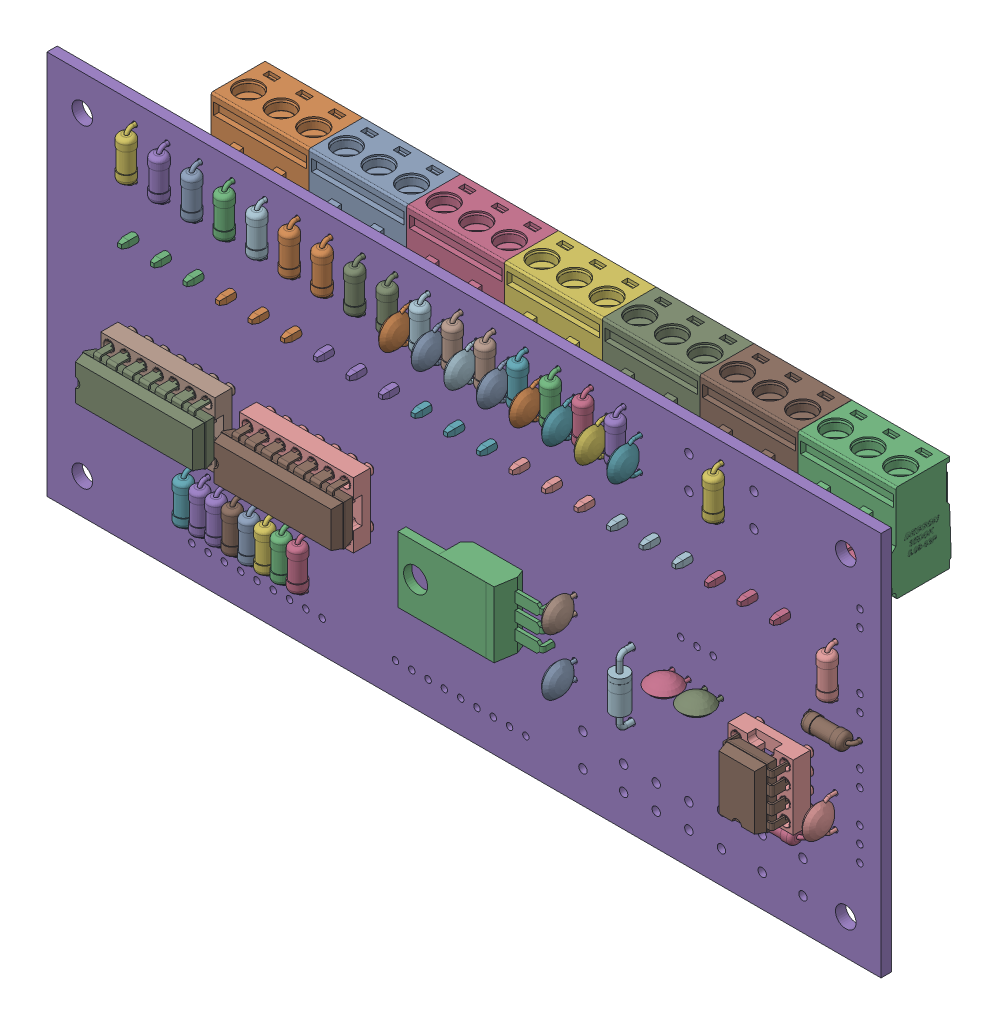
SolidWorks assembly minilab.step, configuration Predeterminado. Lengths in mm.
Overall size (130 60 30.78).
129 component instances, 13 part files, 0 mates.
Components (placement in the parent):
- C_Disc_D5.0mm_W2.5mm_P2.50mm.step-1: C_Disc_D5.0mm_W2.5mm_P2.50mm.step [Predeterminado] at (175.26 -113.03 1.65) x (0 -1 0) z (0 0 1) size (5 2.5 7.1)
  - SOLID.step-1: SOLID.step [Predeterminado] at origin size (5 2.5 7.1)
- C_Disc_D5.0mm_W2.5mm_P5.00mm.step-1: C_Disc_D5.0mm_W2.5mm_P5.00mm.step [Predeterminado] at (170.18 -82.55 1.65) x (0 1 0) z (0 0 1) size (5.5 2.5 7.1)
  - SOLID-0.step-1: SOLID-0.step [Predeterminado] at origin size (5.5 2.5 7.1)
- R_Axial_DIN0207_L6.3mm_D2.5mm_P7.62mm_Horizontal.step-1: R_Axial_DIN0207_L6.3mm_D2.5mm_P7.62mm_Horizontal.step [Predeterminado] at (121.92 -82.55 1.65) x (0 1 0) z (0 0 1) size (8.22 2.5 5.5)
  - SOLID-1.step-1: SOLID-1.step [Predeterminado] at origin size (8.22 2.5 5.5)
- C_Disc_D5.0mm_W2.5mm_P2.50mm.step_2-1: C_Disc_D5.0mm_W2.5mm_P2.50mm.step_2 [Predeterminado] at (190.52 -106.68 1.65) size (5 2.5 7.1)
  - SOLID.step-1: SOLID.step [Predeterminado] at origin size (5 2.5 7.1)
- R_Axial_DIN0207_L6.3mm_D2.5mm_P7.62mm_Horizontal.step_2-1: R_Axial_DIN0207_L6.3mm_D2.5mm_P7.62mm_Horizontal.step_2 [Predeterminado] at (182.88 -74.93 1.65) x (0 -1 0) z (0 0 1) size (8.22 2.5 5.5)
  - SOLID-1.step-1: SOLID-1.step [Predeterminado] at origin size (8.22 2.5 5.5)
- R_Axial_DIN0207_L6.3mm_D2.5mm_P7.62mm_Horizontal.step_3-1: R_Axial_DIN0207_L6.3mm_D2.5mm_P7.62mm_Horizontal.step_3 [Predeterminado] at (198.12 -82.55 1.65) x (0 1 0) z (0 0 1) size (8.22 2.5 5.5)
  - SOLID-1.step-1: SOLID-1.step [Predeterminado] at origin size (8.22 2.5 5.5)
- C_Disc_D5.0mm_W2.5mm_P5.00mm.step_2-1: C_Disc_D5.0mm_W2.5mm_P5.00mm.step_2 [Predeterminado] at (175.26 -82.51 1.65) x (0 1 0) z (0 0 1) size (5.5 2.5 7.1)
  - SOLID-0.step-1: SOLID-0.step [Predeterminado] at origin size (5.5 2.5 7.1)
- DIP-14_W7.62mm_Socket.step-1: DIP-14_W7.62mm_Socket.step [Predeterminado] at (106.675 -110.48 1.65) x (0 1 0) z (0 0 1) size (10.16 17.78 7.79)
  - SOLID-2.step-1: SOLID-2.step [Predeterminado] at origin size (10.16 17.78 7.79)
- DIP-14_W7.62mm.step-1: DIP-14_W7.62mm.step [Predeterminado] at (106.675 -110.48 5.65) x (0 1 0) z (0 0 1) size (7.87 19.05 6.98)
  - SOLID-3.step-1: SOLID-3.step [Predeterminado] at origin size (7.87 19.05 6.98)
- DIP-8_W7.62mm_Socket.step-1: DIP-8_W7.62mm_Socket.step [Predeterminado] at (212.06 -114.3 1.65) x (-1 0 0) z (0 0 1) size (10.16 10.16 7.79)
  - SOLID-4.step-1: SOLID-4.step [Predeterminado] at origin size (10.16 10.16 7.79)
- DIP-8_W7.62mm.step-1: DIP-8_W7.62mm.step [Predeterminado] at (212.06 -114.3 5.65) x (-1 0 0) z (0 0 1) size (7.87 9.27 6.98)
  - SOLID-5.step-1: SOLID-5.step [Predeterminado] at origin size (7.87 9.27 6.98)
- R_Axial_DIN0207_L6.3mm_D2.5mm_P7.62mm_Horizontal.step_4-1: R_Axial_DIN0207_L6.3mm_D2.5mm_P7.62mm_Horizontal.step_4 [Predeterminado] at (127 -82.55 1.65) x (0 1 0) z (0 0 1) size (8.22 2.5 5.5)
  - SOLID-1.step-1: SOLID-1.step [Predeterminado] at origin size (8.22 2.5 5.5)
- R_Axial_DIN0207_L6.3mm_D2.5mm_P7.62mm_Horizontal.step_5-1: R_Axial_DIN0207_L6.3mm_D2.5mm_P7.62mm_Horizontal.step_5 [Predeterminado] at (125.73 -116.84 1.65) x (0 -1 0) z (0 0 1) size (8.22 2.5 5.5)
  - SOLID-1.step-1: SOLID-1.step [Predeterminado] at origin size (8.22 2.5 5.5)
- C_Disc_D5.0mm_W2.5mm_P5.00mm.step_3-1: C_Disc_D5.0mm_W2.5mm_P5.00mm.step_3 [Predeterminado] at (149.86 -82.55 1.65) x (0 1 0) z (0 0 1) size (5.5 2.5 7.1)
  - SOLID-0.step-1: SOLID-0.step [Predeterminado] at origin size (5.5 2.5 7.1)
- TO-220-3_Horizontal_TabUp.step-1: TO-220-3_Horizontal_TabUp.step [Predeterminado] at (171.66 -107.46 1.65) x (0 -1 0) z (0 0 1) size (10.25 19.74 12.58)
  - SOLID-6.step-1: SOLID-6.step [Predeterminado] at origin size (10.25 19.74 12.58)
- R_Axial_DIN0207_L6.3mm_D2.5mm_P7.62mm_Horizontal.step_6-1: R_Axial_DIN0207_L6.3mm_D2.5mm_P7.62mm_Horizontal.step_6 [Predeterminado] at (133.35 -116.84 1.65) x (0 -1 0) z (0 0 1) size (8.22 2.5 5.5)
  - SOLID-1.step-1: SOLID-1.step [Predeterminado] at origin size (8.22 2.5 5.5)
- R_Axial_DIN0207_L6.3mm_D2.5mm_P7.62mm_Horizontal.step_7-1: R_Axial_DIN0207_L6.3mm_D2.5mm_P7.62mm_Horizontal.step_7 [Predeterminado] at (120.65 -116.84 1.65) x (0 -1 0) z (0 0 1) size (8.22 2.5 5.5)
  - SOLID-1.step-1: SOLID-1.step [Predeterminado] at origin size (8.22 2.5 5.5)
- C_Disc_D5.0mm_W2.5mm_P5.00mm.step_4-1: C_Disc_D5.0mm_W2.5mm_P5.00mm.step_4 [Predeterminado] at (180.34 -82.51 1.65) x (0 1 0) z (0 0 1) size (5.5 2.5 7.1)
  - SOLID-0.step-1: SOLID-0.step [Predeterminado] at origin size (5.5 2.5 7.1)
- R_Axial_DIN0207_L6.3mm_D2.5mm_P7.62mm_Horizontal.step_8-1: R_Axial_DIN0207_L6.3mm_D2.5mm_P7.62mm_Horizontal.step_8 [Predeterminado] at (115.57 -116.84 1.65) x (0 -1 0) z (0 0 1) size (8.22 2.5 5.5)
  - SOLID-1.step-1: SOLID-1.step [Predeterminado] at origin size (8.22 2.5 5.5)
- R_Axial_DIN0207_L6.3mm_D2.5mm_P7.62mm_Horizontal.step_9-1: R_Axial_DIN0207_L6.3mm_D2.5mm_P7.62mm_Horizontal.step_9 [Predeterminado] at (157.48 -74.93 1.65) x (0 -1 0) z (0 0 1) size (8.22 2.5 5.5)
  - SOLID-1.step-1: SOLID-1.step [Predeterminado] at origin size (8.22 2.5 5.5)
- R_Axial_DIN0207_L6.3mm_D2.5mm_P7.62mm_Horizontal.step_10-1: R_Axial_DIN0207_L6.3mm_D2.5mm_P7.62mm_Horizontal.step_10 [Predeterminado] at (142.24 -82.55 1.65) x (0 1 0) z (0 0 1) size (8.22 2.5 5.5)
  - SOLID-1.step-1: SOLID-1.step [Predeterminado] at origin size (8.22 2.5 5.5)
- C_Disc_D5.0mm_W2.5mm_P5.00mm.step_5-1: C_Disc_D5.0mm_W2.5mm_P5.00mm.step_5 [Predeterminado] at (215.88 -110.54 1.65) x (0 -1 0) z (0 0 1) size (5.5 2.5 7.1)
  - SOLID-0.step-1: SOLID-0.step [Predeterminado] at origin size (5.5 2.5 7.1)
- R_Axial_DIN0207_L6.3mm_D2.5mm_P7.62mm_Horizontal.step_11-1: R_Axial_DIN0207_L6.3mm_D2.5mm_P7.62mm_Horizontal.step_11 [Predeterminado] at (123.19 -116.84 1.65) x (0 -1 0) z (0 0 1) size (8.22 2.5 5.5)
  - SOLID-1.step-1: SOLID-1.step [Predeterminado] at origin size (8.22 2.5 5.5)
- D_DO-41_SOD81_P10.16mm_Horizontal.step-1: D_DO-41_SOD81_P10.16mm_Horizontal.step [Predeterminado] at (184.15 -106.68 1.65) x (0 -1 0) z (0 0 1) size (10.96 2.72 5.71)
  - SOLID-7.step-1: SOLID-7.step [Predeterminado] at origin size (10.96 2.72 5.71)
- R_Axial_DIN0207_L6.3mm_D2.5mm_P7.62mm_Horizontal.step_12-1: R_Axial_DIN0207_L6.3mm_D2.5mm_P7.62mm_Horizontal.step_12 [Predeterminado] at (116.84 -82.55 1.65) x (0 1 0) z (0 0 1) size (8.22 2.5 5.5)
  - SOLID-1.step-1: SOLID-1.step [Predeterminado] at origin size (8.22 2.5 5.5)
- R_Axial_DIN0207_L6.3mm_D2.5mm_P7.62mm_Horizontal.step_13-1: R_Axial_DIN0207_L6.3mm_D2.5mm_P7.62mm_Horizontal.step_13 [Predeterminado] at (132.08 -82.55 1.65) x (0 1 0) z (0 0 1) size (8.22 2.5 5.5)
  - SOLID-1.step-1: SOLID-1.step [Predeterminado] at origin size (8.22 2.5 5.5)
- R_Axial_DIN0207_L6.3mm_D2.5mm_P7.62mm_Horizontal.step_14-1: R_Axial_DIN0207_L6.3mm_D2.5mm_P7.62mm_Horizontal.step_14 [Predeterminado] at (172.72 -74.93 1.65) x (0 -1 0) z (0 0 1) size (8.22 2.5 5.5)
  - SOLID-1.step-1: SOLID-1.step [Predeterminado] at origin size (8.22 2.5 5.5)
- R_Axial_DIN0207_L6.3mm_D2.5mm_P7.62mm_Horizontal.step_15-1: R_Axial_DIN0207_L6.3mm_D2.5mm_P7.62mm_Horizontal.step_15 [Predeterminado] at (177.8 -74.93 1.65) x (0 -1 0) z (0 0 1) size (8.22 2.5 5.5)
  - SOLID-1.step-1: SOLID-1.step [Predeterminado] at origin size (8.22 2.5 5.5)
- R_Axial_DIN0207_L6.3mm_D2.5mm_P7.62mm_Horizontal.step_16-1: R_Axial_DIN0207_L6.3mm_D2.5mm_P7.62mm_Horizontal.step_16 [Predeterminado] at (111.76 -82.55 1.65) x (0 1 0) z (0 0 1) size (8.22 2.5 5.5)
  - SOLID-1.step-1: SOLID-1.step [Predeterminado] at origin size (8.22 2.5 5.5)
- R_Axial_DIN0207_L6.3mm_D2.5mm_P7.62mm_Horizontal.step_17-1: R_Axial_DIN0207_L6.3mm_D2.5mm_P7.62mm_Horizontal.step_17 [Predeterminado] at (128.27 -116.84 1.65) x (0 -1 0) z (0 0 1) size (8.22 2.5 5.5)
  - SOLID-1.step-1: SOLID-1.step [Predeterminado] at origin size (8.22 2.5 5.5)
- C_Disc_D5.0mm_W2.5mm_P5.00mm.step_6-1: C_Disc_D5.0mm_W2.5mm_P5.00mm.step_6 [Predeterminado] at (185.42 -82.51 1.65) x (0 1 0) z (0 0 1) size (5.5 2.5 7.1)
  - SOLID-0.step-1: SOLID-0.step [Predeterminado] at origin size (5.5 2.5 7.1)
- C_Disc_D5.0mm_W2.5mm_P2.50mm.step_3-1: C_Disc_D5.0mm_W2.5mm_P2.50mm.step_3 [Predeterminado] at (175.26 -106.68 1.65) x (0 1 0) z (0 0 1) size (5 2.5 7.1)
  - SOLID.step-1: SOLID.step [Predeterminado] at origin size (5 2.5 7.1)
- C_Disc_D5.0mm_W2.5mm_P2.50mm.step_4-1: C_Disc_D5.0mm_W2.5mm_P2.50mm.step_4 [Predeterminado] at (198.08 -106.68 1.65) x (-1 0 0) z (0 0 1) size (5 2.5 7.1)
  - SOLID.step-1: SOLID.step [Predeterminado] at origin size (5 2.5 7.1)
- R_Axial_DIN0207_L6.3mm_D2.5mm_P7.62mm_Horizontal.step_18-1: R_Axial_DIN0207_L6.3mm_D2.5mm_P7.62mm_Horizontal.step_18 [Predeterminado] at (215.9 -90.17 1.65) x (0 -1 0) z (0 0 1) size (8.22 2.5 5.5)
  - SOLID-1.step-1: SOLID-1.step [Predeterminado] at origin size (8.22 2.5 5.5)
- R_Axial_DIN0207_L6.3mm_D2.5mm_P7.62mm_Horizontal.step_19-1: R_Axial_DIN0207_L6.3mm_D2.5mm_P7.62mm_Horizontal.step_19 [Predeterminado] at (219.69 -101.61 1.65) x (-1 0 0) z (0 0 1) size (8.22 2.5 5.5)
  - SOLID-1.step-1: SOLID-1.step [Predeterminado] at origin size (8.22 2.5 5.5)
- C_Disc_D5.0mm_W2.5mm_P5.00mm.step_7-1: C_Disc_D5.0mm_W2.5mm_P5.00mm.step_7 [Predeterminado] at (160.02 -82.55 1.65) x (0 1 0) z (0 0 1) size (5.5 2.5 7.1)
  - SOLID-0.step-1: SOLID-0.step [Predeterminado] at origin size (5.5 2.5 7.1)
- C_Disc_D5.0mm_W2.5mm_P5.00mm.step_8-1: C_Disc_D5.0mm_W2.5mm_P5.00mm.step_8 [Predeterminado] at (165.1 -82.55 1.65) x (0 1 0) z (0 0 1) size (5.5 2.5 7.1)
  - SOLID-0.step-1: SOLID-0.step [Predeterminado] at origin size (5.5 2.5 7.1)
- R_Axial_DIN0207_L6.3mm_D2.5mm_P7.62mm_Horizontal.step_20-1: R_Axial_DIN0207_L6.3mm_D2.5mm_P7.62mm_Horizontal.step_20 [Predeterminado] at (137.16 -82.55 1.65) x (0 1 0) z (0 0 1) size (8.22 2.5 5.5)
  - SOLID-1.step-1: SOLID-1.step [Predeterminado] at origin size (8.22 2.5 5.5)
- R_Axial_DIN0207_L6.3mm_D2.5mm_P7.62mm_Horizontal.step_21-1: R_Axial_DIN0207_L6.3mm_D2.5mm_P7.62mm_Horizontal.step_21 [Predeterminado] at (130.81 -116.84 1.65) x (0 -1 0) z (0 0 1) size (8.22 2.5 5.5)
  - SOLID-1.step-1: SOLID-1.step [Predeterminado] at origin size (8.22 2.5 5.5)
- R_Axial_DIN0207_L6.3mm_D2.5mm_P7.62mm_Horizontal.step_22-1: R_Axial_DIN0207_L6.3mm_D2.5mm_P7.62mm_Horizontal.step_22 [Predeterminado] at (204.45 -118.12 1.65) size (8.22 2.5 5.5)
  - SOLID-1.step-1: SOLID-1.step [Predeterminado] at origin size (8.22 2.5 5.5)
- R_Axial_DIN0207_L6.3mm_D2.5mm_P7.62mm_Horizontal.step_23-1: R_Axial_DIN0207_L6.3mm_D2.5mm_P7.62mm_Horizontal.step_23 [Predeterminado] at (118.11 -116.84 1.65) x (0 -1 0) z (0 0 1) size (8.22 2.5 5.5)
  - SOLID-1.step-1: SOLID-1.step [Predeterminado] at origin size (8.22 2.5 5.5)
- R_Axial_DIN0207_L6.3mm_D2.5mm_P7.62mm_Horizontal.step_24-1: R_Axial_DIN0207_L6.3mm_D2.5mm_P7.62mm_Horizontal.step_24 [Predeterminado] at (106.68 -82.55 1.65) x (0 1 0) z (0 0 1) size (8.22 2.5 5.5)
  - SOLID-1.step-1: SOLID-1.step [Predeterminado] at origin size (8.22 2.5 5.5)
- R_Axial_DIN0207_L6.3mm_D2.5mm_P7.62mm_Horizontal.step_25-1: R_Axial_DIN0207_L6.3mm_D2.5mm_P7.62mm_Horizontal.step_25 [Predeterminado] at (167.64 -74.93 1.65) x (0 -1 0) z (0 0 1) size (8.22 2.5 5.5)
  - SOLID-1.step-1: SOLID-1.step [Predeterminado] at origin size (8.22 2.5 5.5)
- R_Axial_DIN0207_L6.3mm_D2.5mm_P7.62mm_Horizontal.step_26-1: R_Axial_DIN0207_L6.3mm_D2.5mm_P7.62mm_Horizontal.step_26 [Predeterminado] at (162.56 -74.93 1.65) x (0 -1 0) z (0 0 1) size (8.22 2.5 5.5)
  - SOLID-1.step-1: SOLID-1.step [Predeterminado] at origin size (8.22 2.5 5.5)
- R_Axial_DIN0207_L6.3mm_D2.5mm_P7.62mm_Horizontal.step_27-1: R_Axial_DIN0207_L6.3mm_D2.5mm_P7.62mm_Horizontal.step_27 [Predeterminado] at (147.32 -74.93 1.65) x (0 -1 0) z (0 0 1) size (8.22 2.5 5.5)
  - SOLID-1.step-1: SOLID-1.step [Predeterminado] at origin size (8.22 2.5 5.5)
- DIP-14_W7.62mm_Socket.step_2-1: DIP-14_W7.62mm_Socket.step_2 [Predeterminado] at (128.265 -110.48 1.65) x (0 1 0) z (0 0 1) size (10.16 17.78 7.79)
  - SOLID-2.step-1: SOLID-2.step [Predeterminado] at origin size (10.16 17.78 7.79)
- DIP-14_W7.62mm.step_2-1: DIP-14_W7.62mm.step_2 [Predeterminado] at (128.265 -110.48 5.65) x (0 1 0) z (0 0 1) size (7.87 19.05 6.98)
  - SOLID-3.step-1: SOLID-3.step [Predeterminado] at origin size (7.87 19.05 6.98)
- R_Axial_DIN0207_L6.3mm_D2.5mm_P7.62mm_Horizontal.step_28-1: R_Axial_DIN0207_L6.3mm_D2.5mm_P7.62mm_Horizontal.step_28 [Predeterminado] at (152.4 -74.93 1.65) x (0 -1 0) z (0 0 1) size (8.22 2.5 5.5)
  - SOLID-1.step-1: SOLID-1.step [Predeterminado] at origin size (8.22 2.5 5.5)
- C_Disc_D5.0mm_W2.5mm_P5.00mm.step_9-1: C_Disc_D5.0mm_W2.5mm_P5.00mm.step_9 [Predeterminado] at (154.94 -82.55 1.65) x (0 1 0) z (0 0 1) size (5.5 2.5 7.1)
  - SOLID-0.step-1: SOLID-0.step [Predeterminado] at origin size (5.5 2.5 7.1)
- 2EDGK-5.08-03P-14-00AH.step-1: 2EDGK-5.08-03P-14-00AH.step [Predeterminado] at (104.14 -94.21 -4.05) x (1 0 0) z (0 1 0) size (15.24 17.4 15.1)
  - SOLID-8.step-1: SOLID-8.step [Predeterminado] at origin size (15.24 17.4 15.1)
- 2EDGV-5.08-03P-14-00AH.step-1: 2EDGV-5.08-03P-14-00AH.step [Predeterminado] at (104.14 -93.91 -0.05) x (1 0 0) z (0 1 0) size (15.24 16.1 8.2)
  - SOLID-9.step-1: SOLID-9.step [Predeterminado] at origin size (15.24 16.1 8.2)
- 2EDGK-5.08-03P-14-00AH.step_2-1: 2EDGK-5.08-03P-14-00AH.step_2 [Predeterminado] at (134.62 -94.21 -4.05) x (1 0 0) z (0 1 0) size (15.24 17.4 15.1)
  - SOLID-8.step-1: SOLID-8.step [Predeterminado] at origin size (15.24 17.4 15.1)
- 2EDGV-5.08-03P-14-00AH.step_2-1: 2EDGV-5.08-03P-14-00AH.step_2 [Predeterminado] at (134.62 -93.91 -0.05) x (1 0 0) z (0 1 0) size (15.24 16.1 8.2)
  - SOLID-9.step-1: SOLID-9.step [Predeterminado] at origin size (15.24 16.1 8.2)
- 2EDGK-5.08-03P-14-00AH.step_3-1: 2EDGK-5.08-03P-14-00AH.step_3 [Predeterminado] at (149.86 -94.21 -4.05) x (1 0 0) z (0 1 0) size (15.24 17.4 15.1)
  - SOLID-8.step-1: SOLID-8.step [Predeterminado] at origin size (15.24 17.4 15.1)
- 2EDGV-5.08-03P-14-00AH.step_3-1: 2EDGV-5.08-03P-14-00AH.step_3 [Predeterminado] at (149.86 -93.91 -0.05) x (1 0 0) z (0 1 0) size (15.24 16.1 8.2)
  - SOLID-9.step-1: SOLID-9.step [Predeterminado] at origin size (15.24 16.1 8.2)
- SOIC-8-1EP_3.9x4.9mm_P1.27mm_EP2.35x2.35mm.step-1: SOIC-8-1EP_3.9x4.9mm_P1.27mm_EP2.35x2.35mm.step [Predeterminado] at (194.31 -114.3 -0.05) x (-1 0 0) z (0 0 -1) size (6 4.9 1.75)
  - SOLID-10.step-1: SOLID-10.step [Predeterminado] at origin size (6 4.9 1.75)
- 2EDGK-5.08-03P-14-00AH.step_4-1: 2EDGK-5.08-03P-14-00AH.step_4 [Predeterminado] at (165.1 -94.21 -4.05) x (1 0 0) z (0 1 0) size (15.24 17.4 15.1)
  - SOLID-8.step-1: SOLID-8.step [Predeterminado] at origin size (15.24 17.4 15.1)
- 2EDGV-5.08-03P-14-00AH.step_4-1: 2EDGV-5.08-03P-14-00AH.step_4 [Predeterminado] at (165.1 -93.91 -0.05) x (1 0 0) z (0 1 0) size (15.24 16.1 8.2)
  - SOLID-9.step-1: SOLID-9.step [Predeterminado] at origin size (15.24 16.1 8.2)
- 2EDGK-5.08-03P-14-00AH.step_5-1: 2EDGK-5.08-03P-14-00AH.step_5 [Predeterminado] at (180.34 -94.21 -4.05) x (1 0 0) z (0 1 0) size (15.24 17.4 15.1)
  - SOLID-8.step-1: SOLID-8.step [Predeterminado] at origin size (15.24 17.4 15.1)
- 2EDGV-5.08-03P-14-00AH.step_5-1: 2EDGV-5.08-03P-14-00AH.step_5 [Predeterminado] at (180.34 -93.91 -0.05) x (1 0 0) z (0 1 0) size (15.24 16.1 8.2)
  - SOLID-9.step-1: SOLID-9.step [Predeterminado] at origin size (15.24 16.1 8.2)
- 2EDGK-5.08-03P-14-00AH.step_6-1: 2EDGK-5.08-03P-14-00AH.step_6 [Predeterminado] at (119.38 -94.21 -4.05) x (1 0 0) z (0 1 0) size (15.24 17.4 15.1)
  - SOLID-8.step-1: SOLID-8.step [Predeterminado] at origin size (15.24 17.4 15.1)
- 2EDGV-5.08-03P-14-00AH.step_6-1: 2EDGV-5.08-03P-14-00AH.step_6 [Predeterminado] at (119.38 -93.91 -0.05) x (1 0 0) z (0 1 0) size (15.24 16.1 8.2)
  - SOLID-9.step-1: SOLID-9.step [Predeterminado] at origin size (15.24 16.1 8.2)
- 2EDGK-5.08-03P-14-00AH.step_7-1: 2EDGK-5.08-03P-14-00AH.step_7 [Predeterminado] at (195.615 -94.21 -4.05) x (1 0 0) z (0 1 0) size (15.24 17.4 15.1)
  - SOLID-8.step-1: SOLID-8.step [Predeterminado] at origin size (15.24 17.4 15.1)
- 2EDGV-5.08-03P-14-00AH.step_7-1: 2EDGV-5.08-03P-14-00AH.step_7 [Predeterminado] at (195.575 -93.91 -0.05) x (1 0 0) z (0 1 0) size (15.24 16.1 8.2)
  - SOLID-9.step-1: SOLID-9.step [Predeterminado] at origin size (15.24 16.1 8.2)
- minilab PCB.step-1: minilab PCB.step [Predeterminado] at origin size (130 60 1.6)
